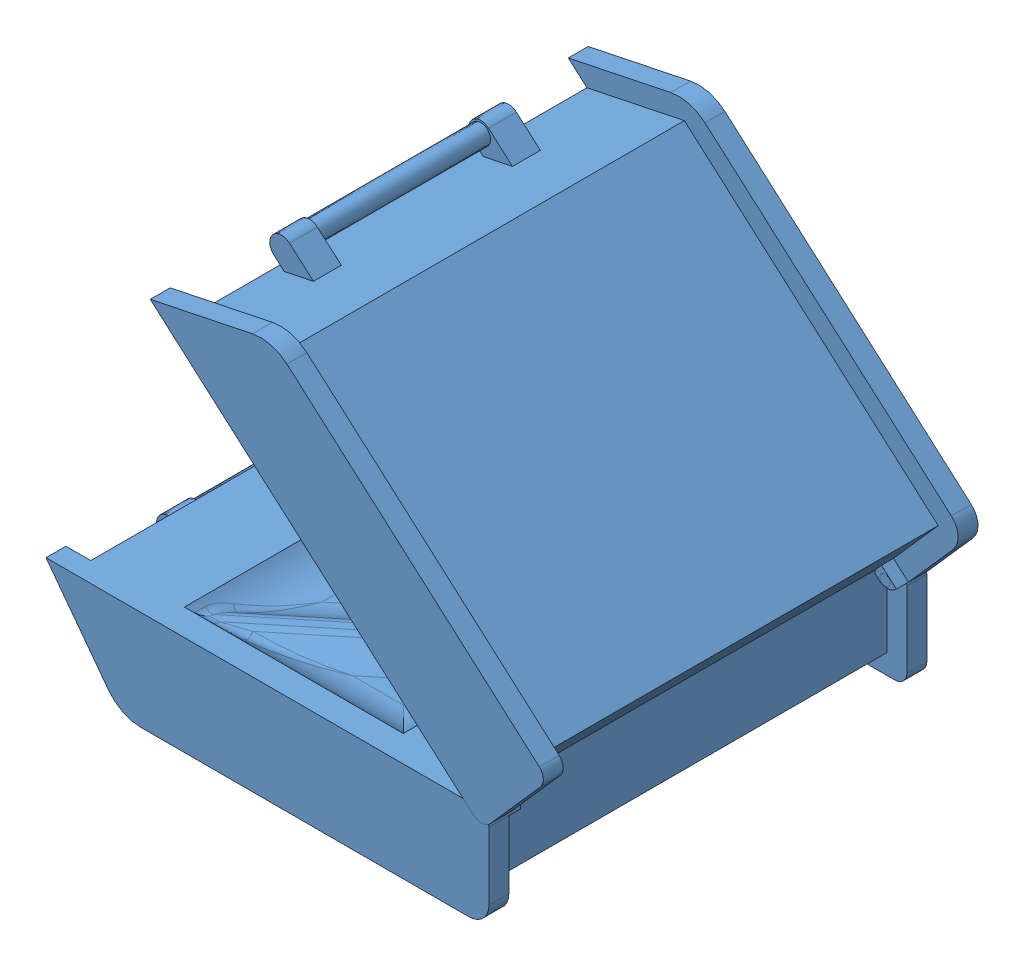
SolidWorks assembly Assem1, configuration Default. Lengths in mm.
Overall size (126.17 113.05 110).
2 component instances, 1 part files, 2 mates.
Components (placement in the parent):
- Tosti ijzer onderkant-1: Tosti ijzer onderkant [Default] at origin size (111.25 25.09 110)
- Tosti ijzer onderkant-2: Tosti ijzer onderkant [Default] at (12.8607 34.0292 100) x (0.750039 -0.661393 0) z (0 0 -1) size (111.25 25.09 110)
Mates (geometry in assembly coordinates):
- Concentric1: concentric aligned: cylinder of Tosti ijzer onderkant-1 through (2.5 18.5 97) axis (0 0 1) radius 1.25; cylinder of Tosti ijzer onderkant-2 through (2.5 18.5 97) axis (0 0 1) radius 1.25
- Coincident1: coincident aligned: plane of Tosti ijzer onderkant-1 through (-104 22 105) normal (0 0 1); plane of Tosti ijzer onderkant-2 through (-79.694 86.3133 105) normal (0 0 1)
